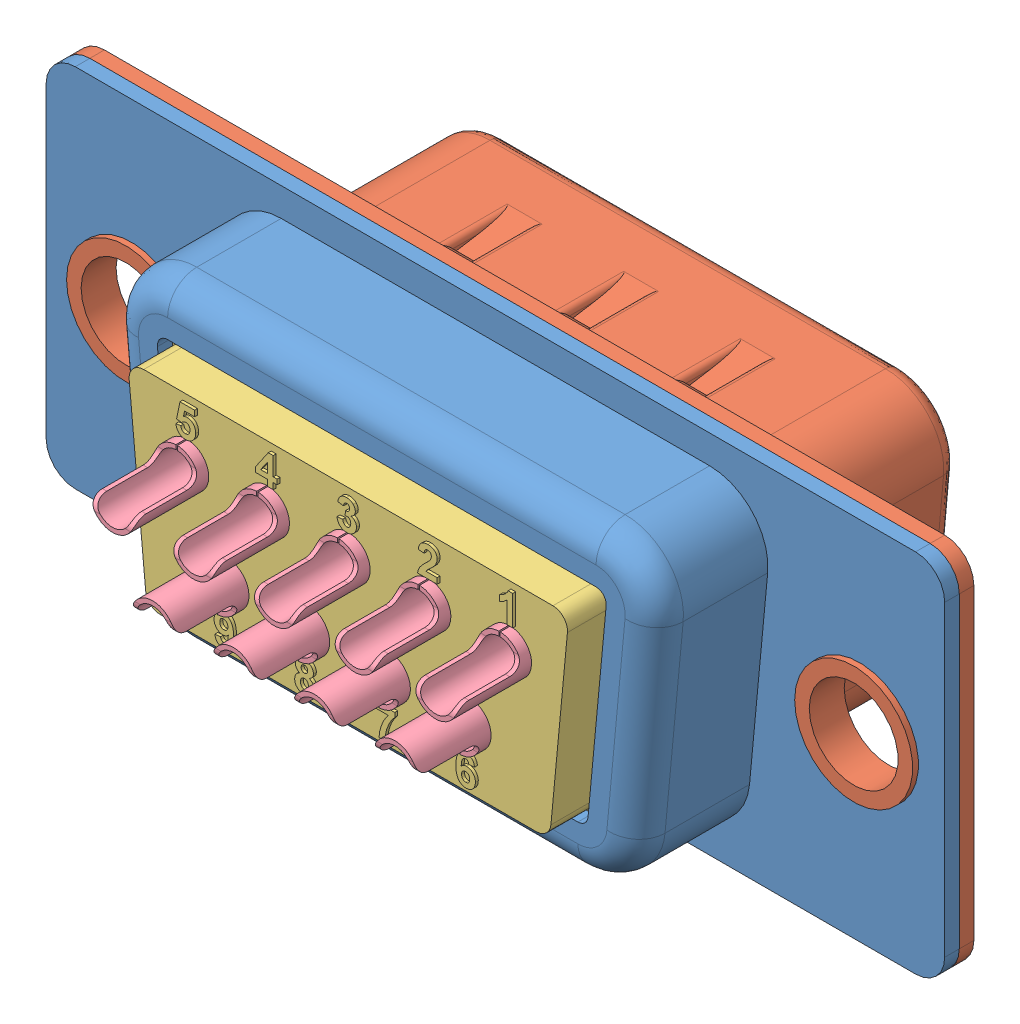
SolidWorks assembly Assem dt, configuration Default. Lengths in mm.
Overall size (30.84 17.69 14.7).
12 component instances, 4 part files, 35 mates.
Components (placement in the parent):
- D-T -1-1: D-T -1 [Default] at (15.4076 17.3206 20.7832) size (30.84 12.55 4.4)
- D-T-1: D-T [Default] at (15.4076 17.3206 20.7832) x (-1 0 0) z (0 0 -1) size (30.84 12.55 7.3)
- D-T -2-1: D-T -2 [Default] at (15.4076 17.3206 24.5832) x (-1 0 0) z (0 0 -1) size (16.3 8.2 5.75)
- D-t pin-1: D-t pin [Default] at (9.8676 18.7406 15.6832) size (1.5 1.51 13.2)
- D-t pin-2: D-t pin [Default] at (12.6376 18.7406 15.6832) size (1.5 1.51 13.2)
- D-t pin-3: D-t pin [Default] at (14.0182 15.9006 15.6832) x (-1 0 0) z (0 0 1) size (1.5 1.51 13.2)
- D-t pin-4: D-t pin [Default] at (11.2482 15.9006 15.6832) x (-1 0 0) z (0 0 1) size (1.5 1.51 13.2)
- D-t pin-5: D-t pin [Default] at (18.1776 18.7406 15.6832) size (1.5 1.51 13.2)
- D-t pin-6: D-t pin [Default] at (15.4076 18.7406 15.6832) size (1.5 1.51 13.2)
- D-t pin-7: D-t pin [Default] at (16.7882 15.9006 15.6832) x (-1 0 0) z (0 0 1) size (1.5 1.51 13.2)
- D-t pin-8: D-t pin [Default] at (19.5582 15.9006 15.6832) x (-1 0 0) z (0 0 1) size (1.5 1.51 13.2)
- D-t pin-9: D-t pin [Default] at (20.9476 18.7406 15.6832) size (1.5 1.51 13.2)
Mates (geometry in assembly coordinates):
- Coincident1: coincident anti-aligned: plane of D-T -1-1 through (29.8276 22.5956 20.7832) normal (0 0 -1); plane of D-T-1 through (0.9876 22.5956 20.7832) normal (0 0 1)
- Coincident2: coincident aligned: plane of D-T -1-1 through (30.8276 22.5956 21.2832) normal (1 0 0); plane of D-T-1 through (30.8276 22.5956 20.2832) normal (1 0 0)
- Coincident3: coincident aligned: plane of D-T -1-1 through (0.9876 23.5956 21.2832) normal (0 1 0); plane of D-T-1 through (29.8276 23.5956 20.2832) normal (0 1 0)
- Coincident4: coincident anti-aligned: plane of D-T-1 through (0.9876 22.5956 20.7832) normal (0 0 1); plane of D-T -2-1 through (8.0551 20.6206 20.7832) normal (0 0 -1)
- Width1: width anti-aligned: plane of D-T -2-1 through (8.0551 21.4206 20.7832) normal (0 1 0); plane of D-T -2-1 through (22.1374 13.2206 20.7832) normal (0 -1 0); plane of D-T -1-1 through (22.76 21.4706 2.3982) normal (0 -1 0); plane of D-T -1-1 through (8.6778 13.1706 2.3982) normal (0 1 0)
- Width2: width anti-aligned: plane of D-T -2-1 through (23.5565 20.5455 20.7832) normal (0.99558 -0.093923 0); plane of D-T -2-1 through (7.8813 13.9455 20.7832) normal (-0.99558 -0.093923 0); plane of D-T -1-1 through (22.9836 13.9408 2.3982) normal (-0.99558 0.093923 0); plane of D-T -1-1 through (7.2089 20.5408 2.3982) normal (0.99558 0.093923 0)
- Concentric2: concentric anti-aligned: circle of D-T -2-1; cylinder of D-t pin-1 through (9.8676 18.7406 20.7832) axis (0 0 -1) radius 0.5
- Coincident6: coincident anti-aligned: plane of D-T -2-1 through (9.8676 18.7406 22.5332) normal (0 0 1); plane of D-t pin-1 through (9.8676 18.7406 22.5332) normal (0 0 -1)
- Concentric3: concentric aligned: cylinder of D-T -2-1 through (12.6376 18.7406 28.4545) axis (0 0 -1) radius 0.75; cylinder of D-t pin-2 through (12.6376 18.7406 20.7832) axis (0 0 -1) radius 0.5
- Concentric4: concentric aligned: cylinder of D-T -2-1 through (15.4076 18.7406 28.4545) axis (0 0 -1) radius 0.75; cylinder of D-t pin-6 through (15.4076 18.7406 20.7832) axis (0 0 -1) radius 0.5
- Concentric5: concentric aligned: cylinder of D-T -2-1 through (18.1776 18.7406 28.4545) axis (0 0 -1) radius 0.75; cylinder of D-t pin-5 through (18.1776 18.7406 20.7832) axis (0 0 -1) radius 0.5
- Concentric6: concentric aligned: cylinder of D-T -2-1 through (20.9476 18.7406 28.4545) axis (0 0 -1) radius 0.75; cylinder of D-t pin-9 through (20.9476 18.7406 20.7832) axis (0 0 -1) radius 0.5
- Coincident8: coincident anti-aligned: plane of D-T -2-1 through (12.6376 18.7406 22.5332) normal (0 0 1); plane of D-t pin-2 through (12.6376 18.7406 22.5332) normal (0 0 -1)
- Coincident9: coincident anti-aligned: plane of D-T -2-1 through (15.4076 18.7406 22.5332) normal (0 0 1); plane of D-t pin-6 through (15.4076 18.7406 22.5332) normal (0 0 -1)
- Coincident10: coincident anti-aligned: plane of D-T -2-1 through (18.1776 18.7406 22.5332) normal (0 0 1); plane of D-t pin-5 through (18.1776 18.7406 22.5332) normal (0 0 -1)
- Coincident11: coincident anti-aligned: plane of D-T -2-1 through (20.9476 18.7406 22.5332) normal (0 0 1); plane of D-t pin-9 through (20.9476 18.7406 22.5332) normal (0 0 -1)
- Concentric7: concentric aligned: cylinder of D-T -2-1 through (11.2482 15.9006 28.4545) axis (0 0 -1) radius 0.75; cylinder of D-t pin-4 through (11.2482 15.9006 20.7832) axis (0 0 -1) radius 0.5
- Concentric8: concentric aligned: cylinder of D-T -2-1 through (14.0182 15.9006 28.4545) axis (0 0 -1) radius 0.75; cylinder of D-t pin-3 through (14.0182 15.9006 20.7832) axis (0 0 -1) radius 0.5
- Concentric9: concentric aligned: cylinder of D-T -2-1 through (16.7882 15.9006 28.4545) axis (0 0 -1) radius 0.75; cylinder of D-t pin-7 through (16.7882 15.9006 20.7832) axis (0 0 -1) radius 0.5
- Concentric10: concentric aligned: cylinder of D-T -2-1 through (19.5582 15.9006 28.4545) axis (0 0 -1) radius 0.75; cylinder of D-t pin-8 through (19.5582 15.9006 20.7832) axis (0 0 -1) radius 0.5
- Coincident12: coincident anti-aligned: plane of D-T -2-1 through (19.5582 15.9006 22.5332) normal (0 0 1); plane of D-t pin-8 through (19.5582 15.9006 22.5332) normal (0 0 -1)
- Coincident13: coincident anti-aligned: plane of D-T -2-1 through (16.7882 15.9006 22.5332) normal (0 0 1); plane of D-t pin-7 through (16.7882 15.9006 22.5332) normal (0 0 -1)
- Coincident14: coincident anti-aligned: plane of D-T -2-1 through (14.0182 15.9006 22.5332) normal (0 0 1); plane of D-t pin-3 through (14.0182 15.9006 22.5332) normal (0 0 -1)
- Coincident15: coincident anti-aligned: plane of D-T -2-1 through (11.2482 15.9006 22.5332) normal (0 0 1); plane of D-t pin-4 through (11.2482 15.9006 22.5332) normal (0 0 -1)
- Parallel2: parallel aligned: plane of D-t pin-1 through (9.8426 19.24 16.1832) normal (1 0 0); plane of assembly through (0 0 0) normal (1 0 0)
- Parallel3: parallel aligned: plane of D-t pin-2 through (12.6126 19.24 16.1832) normal (1 0 0); plane of assembly through (0 0 0) normal (1 0 0)
- Parallel4: parallel aligned: plane of D-t pin-6 through (15.3826 19.24 16.1832) normal (1 0 0); plane of assembly through (0 0 0) normal (1 0 0)
- Parallel5: parallel aligned: plane of D-t pin-5 through (18.1526 19.24 16.1832) normal (1 0 0); plane of assembly through (0 0 0) normal (1 0 0)
- Parallel6: parallel aligned: plane of D-t pin-9 through (20.9226 19.24 16.1832) normal (1 0 0); plane of assembly through (0 0 0) normal (1 0 0)
- Parallel7: parallel anti-aligned: plane of D-t pin-8 through (19.5832 15.4013 16.1832) normal (-1 0 0); plane of assembly through (0 0 0) normal (1 0 0)
- Parallel8: parallel anti-aligned: plane of D-t pin-7 through (16.8132 15.4013 16.1832) normal (-1 0 0); plane of assembly through (0 0 0) normal (1 0 0)
- Parallel9: parallel anti-aligned: plane of D-t pin-3 through (14.0432 15.4013 16.1832) normal (-1 0 0); plane of assembly through (0 0 0) normal (1 0 0)
- Parallel10: parallel anti-aligned: plane of D-t pin-4 through (11.2732 15.4013 16.1832) normal (-1 0 0); plane of assembly through (0 0 0) normal (1 0 0)
- Concentric11: concentric aligned: circle of D-T-1; cylinder of ? through (2.9126 17.3206 9.2968) axis (0 0 1) radius 1.525
- Concentric12: concentric anti-aligned: cylinder of D-T-1 through (27.9026 17.3206 25.0966) axis (0 0 -1) radius 1.525; cylinder of ? through (27.9026 17.3206 9.2968) axis (0 0 1) radius 1.525
